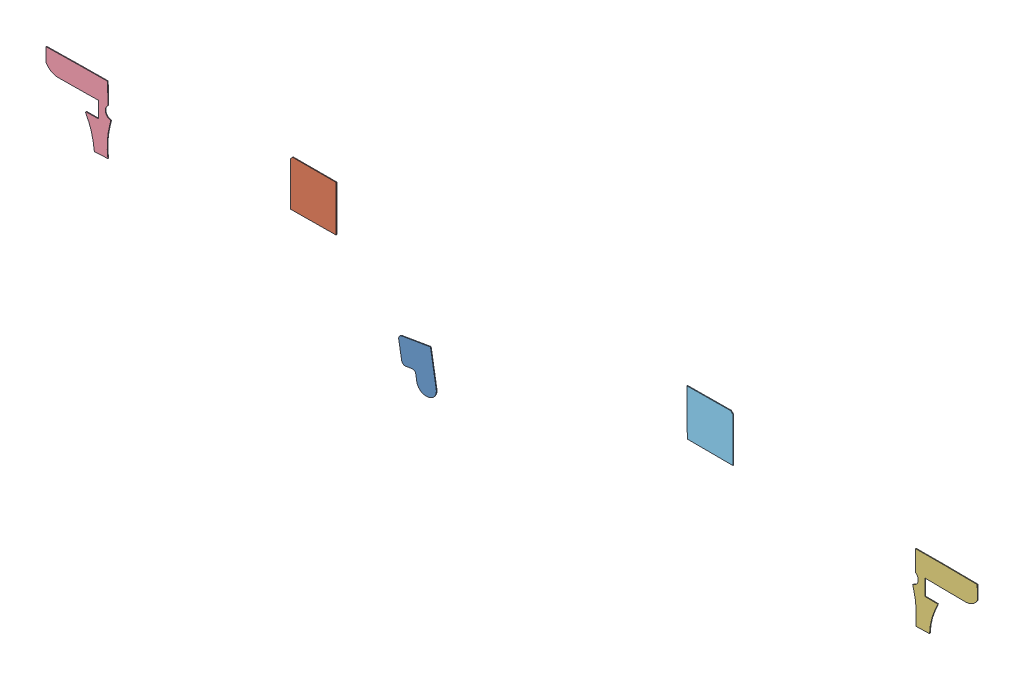
SolidWorks assembly front_flex_v2_1_indiv_parts, configuration Default. Lengths in mm.
Overall size (142.36 20.72 0.8).
32 component instances, 5 part files, 0 mates.
Components (placement in the parent):
- front_flex_v2_1_indiv_parts.step-1: front_flex_v2_1_indiv_parts.step [Default] at origin size (142.36 20.72 0.8)
  - Board.step-1: Board.step [Default] at origin (suppressed, hidden)
  - C1.step-1: C1.step [Default] at origin (suppressed, hidden)
  - C4.step-1: C4.step [Default] at origin (suppressed, hidden)
  - C2.step-1: C2.step [Default] at origin (suppressed, hidden)
  - C3.step-1: C3.step [Default] at origin (suppressed, hidden)
  - C6.step-1: C6.step [Default] at origin (suppressed, hidden)
  - C8.step-1: C8.step [Default] at origin (suppressed, hidden)
  - C7.step-1: C7.step [Default] at origin (suppressed, hidden)
  - C5.step-1: C5.step [Default] at origin (suppressed, hidden)
  - D2.step-1: D2.step [Default] at origin (suppressed, hidden)
  - U2.step-1: U2.step [Default] at origin (suppressed, hidden)
  - IC2.step-1: IC2.step [Default] at origin (suppressed, hidden)
  - IC1.step-1: IC1.step [Default] at origin (suppressed, hidden)
  - R6.step-1: R6.step [Default] at origin (suppressed, hidden)
  - R5.step-1: R5.step [Default] at origin (suppressed, hidden)
  - R4.step-1: R4.step [Default] at origin (suppressed, hidden)
  - J1.step-1: J1.step [Default] at origin (suppressed, hidden)
  - LED4.step-1: LED4.step [Default] at origin (suppressed, hidden)
  - LED2.step-1: LED2.step [Default] at origin (suppressed, hidden)
  - LED3.step-1: LED3.step [Default] at origin (suppressed, hidden)
  - LED1.step-1: LED1.step [Default] at origin (suppressed, hidden)
  - J2.step-1: J2.step [Default] at origin (suppressed, hidden)
  - D1.step-1: D1.step [Default] at origin (suppressed, hidden)
  - Free-Models.step-1: Free-Models.step [Default] at origin size (142.36 20.72 0.8)
    - 10803095376.step-1: 10803095376.step [Default] at (-13.8257 4.2729 0) size (5.77 6.84 0.1)
      - Extruded.step-1: Extruded.step [Default] at origin size (5.77 6.84 0.1)
    - 10803616064.step-1: 10803616064.step [Default] at (-30.4364 18.0523 -0.7) size (6.97 7.04 0.1)
      - Extruded-4.step-1: Extruded-4.step [Default] at origin size (6.97 7.04 0.1)
    - 7856466224.step-1: 7856466224.step [Default] at (66.124 12.2594 -0.7) size (9.88 10.25 0.1)
    - 7856459584.step-1: 7856459584.step [Default] at (-66.3499 12.3269 -0.7) size (9.9 10.31 0.1)
    - 10803618864.step-1: 10803618864.step [Default] at (30.1781 17.9381 -0.7) size (7.07 7.1 0.1)
